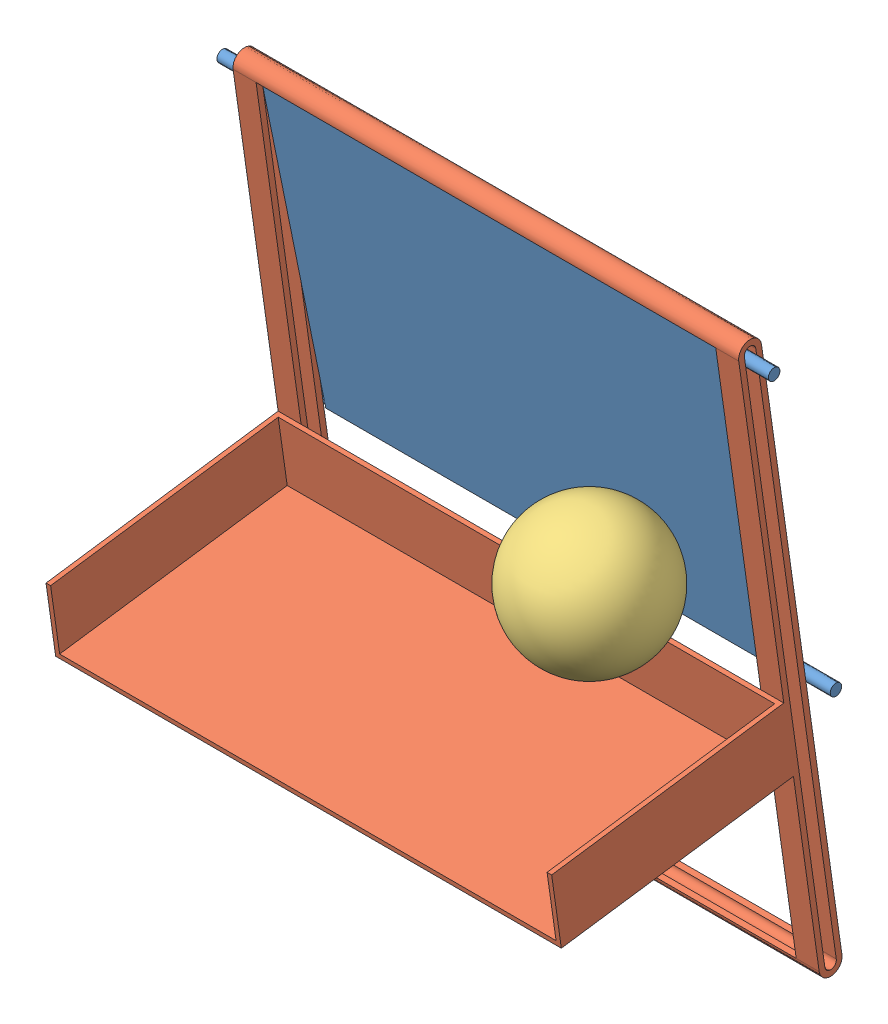
SolidWorks assembly Assemblage1, configuration Défaut. Lengths in mm.
Overall size (240 273.12 147.31).
3 component instances, 3 part files, 4 mates.
Components (placement in the parent):
- Plaque-1: Plaque [Défaut] at (285.1532 122.4565 227.6914) x (1 0 0) z (0 0.979978 0.199105) size (240 5 140)
- Rail-1: Rail [Défaut] at (175.1532 191.7555 244.106) x (1 0 0) z (0 -0.140046 0.990145) size (220 260 112)
- Sphère-1: Sphère [Défaut] at (335.9326 81.0708 249.8959) size (60 60 60)
Mates (geometry in assembly coordinates):
- Tangent1: tangent anti-aligned: cylinder of Plaque-1 through (405.1532 189.1028 238.681) axis (-1 0 0) radius 2.5; plane of Rail-1 through (395.1542 192.8059 236.6799) normal (0 -0.140046 0.990145)
- Tangent2: tangent anti-aligned: cylinder of Plaque-1 through (405.1532 189.1028 238.681) axis (-1 0 0) radius 2.5; plane of Rail-1 through (395.1542 192.8059 236.6799) normal (0 -0.140046 0.990145)
- Coïncidente1: coincident anti-aligned: plane of Plaque-1 through (385.1532 192.0505 236.7288) normal (1 0 0); plane of Rail-1 through (385.1532 219.7647 46.077) normal (-1 0 0)
- Tangent3: tangent anti-aligned: plane of Plaque-1 through (285.1532 122.4565 227.6914) normal (0 -0.199105 0.979978); sphere of Sphère-1
